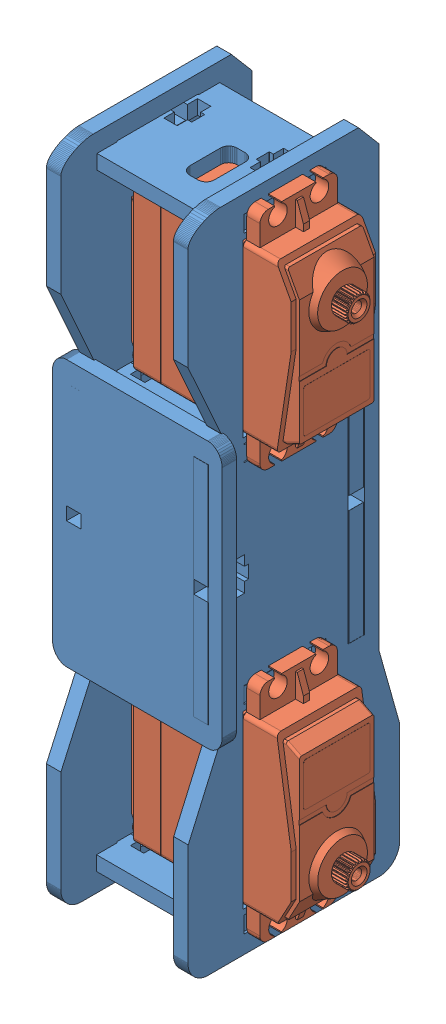
SolidWorks assembly right_shin, configuration Default. Lengths in mm.
Overall size (55.45 159.23 51.17).
3 component instances, 2 part files, 2 mates.
Components (placement in the parent):
- right_shin_100-1: right_shin_100 [Default] at (14.0441 3.8248 109.3106) size (40.95 159.23 51.17)
- SW2019 DS3225MG Servo 25Kg 4.8-6.8V-1: SW2019 DS3225MG Servo 25Kg 4.8-6.8V [Default] at (72.2052 142.3587 136.1362) x (0 -1 0) z (0.999999 0 0.001449) size (54.3 20.4 45.91)
- SW2019 DS3225MG Servo 25Kg 4.8-6.8V-2: SW2019 DS3225MG Servo 25Kg 4.8-6.8V [Default] at (72.1907 23.6409 136.1105) x (0 1 0) z (1 0 0.000023) size (54.3 20.4 45.91)
Mates (geometry in assembly coordinates):
- Coincident1: coincident anti-aligned: line of right_shin_100-1 through (54.3904 152.8909 146.3104) axis (0 -1 0); line of SW2019 DS3225MG Servo 25Kg 4.8-6.8V-1 through (54.3904 113.2587 146.3104) axis (0 1 0)
- Coincident2: coincident anti-aligned: line of right_shin_100-1 through (54.3904 54.3012 146.3101) axis (0 -1 0); line of SW2019 DS3225MG Servo 25Kg 4.8-6.8V-2 through (54.3904 14.5409 146.3101) axis (0 1 0)
